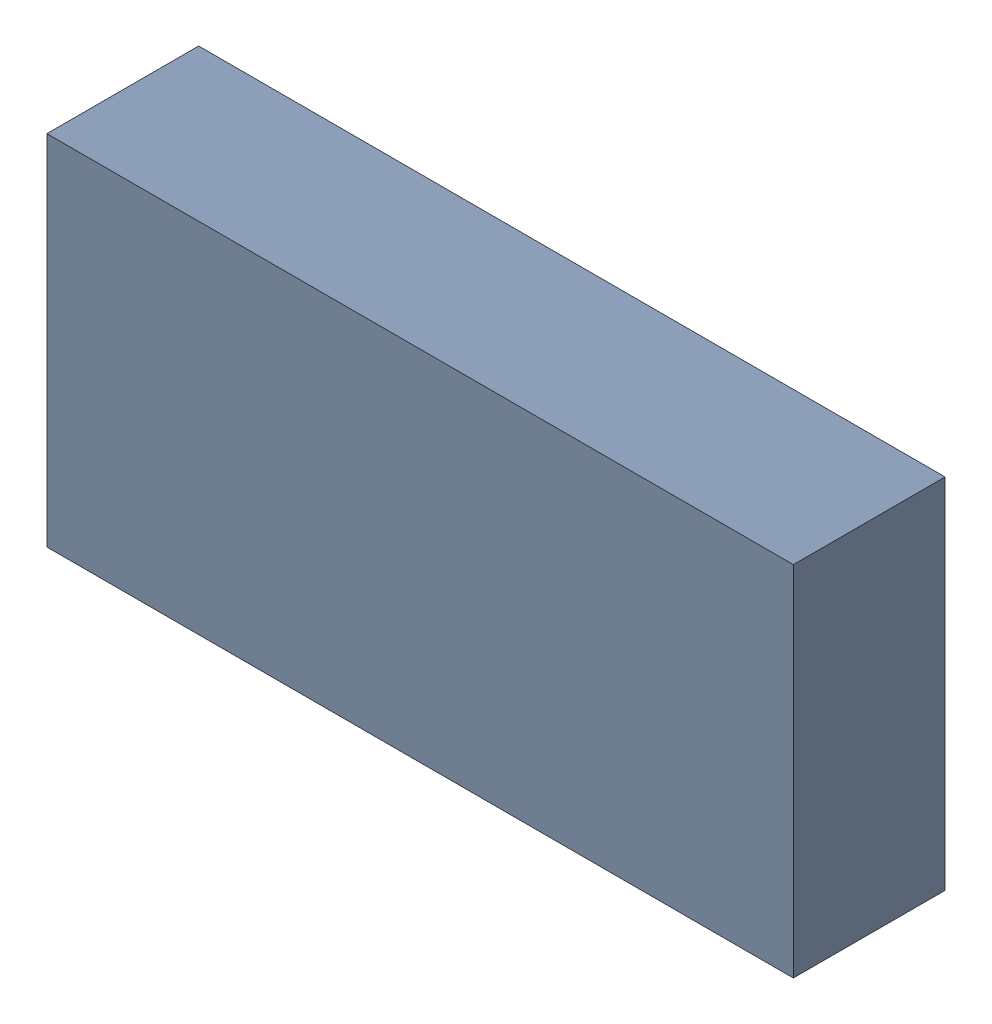
SolidWorks assembly 6327398272, configuration Default. Lengths in mm.
Overall size (1.25 0.6 0.25).
2 component instances, 1 part files, 0 mates.
Components (placement in the parent):
- 6701982208-1:  [Default] at (27.7 14.8 0) (suppressed, hidden)
- Extruded-18-1: Extruded-18 [Default] at origin size (1.25 0.6 0.25)
